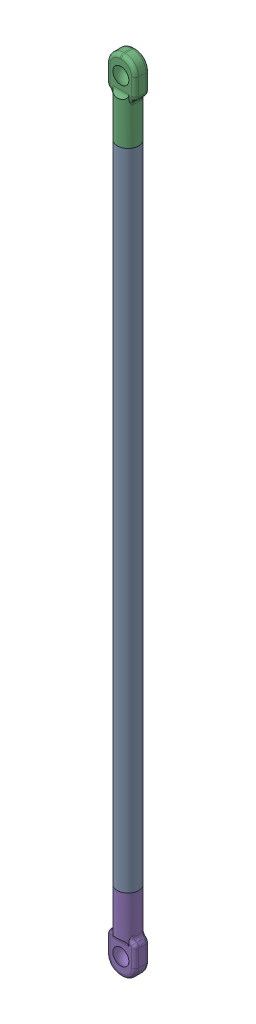
SolidWorks assembly Traxxas 5347 on 180mm Carbon tube, configuration Default. Lengths in mm.
Overall size (8.01 223 6).
5 component instances, 3 part files, 0 mates.
Components (placement in the parent):
- 180mm Carbon tube-1: 180mm Carbon tube [Default] at origin size (6 180 6)
- M4X30 set screw-1: M4X30 set screw [Default] at (0 189.5 0) x (-0.837169 0 -0.546944) z (-0.546944 0 0.837169) size (4 30 4)
- Traxxas 5347-1: Traxxas 5347 [Default] at (0 181.5 0) x (0 0 1) z (-1 0 0) size (6 21.5 8.01)
- M4X30 set screw-2: M4X30 set screw [Default] at (0 -9.5 0) size (4 30 4)
- Traxxas 5347-2: Traxxas 5347 [Default] at (0 -1.5 0) x (0 0 -1) z (-1 0 0) size (6 21.5 8.01)
